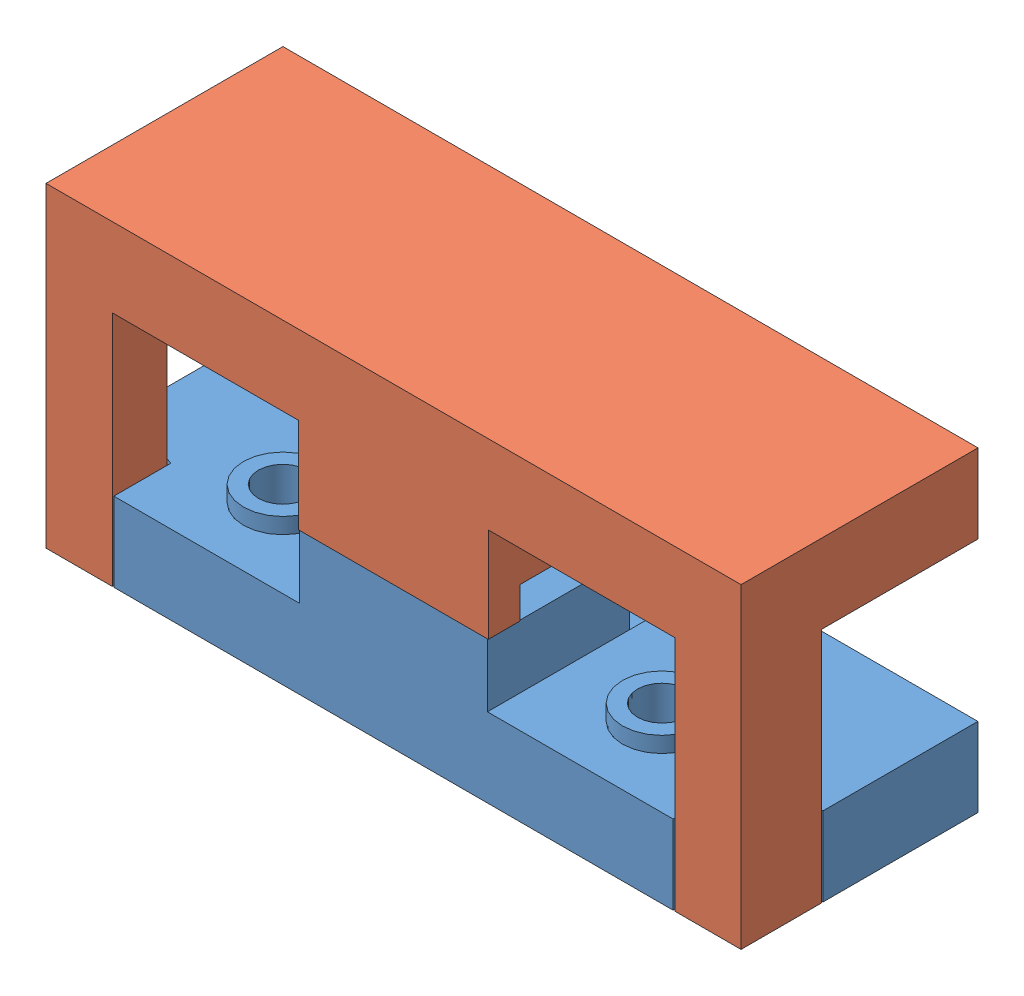
SolidWorks assembly Assem2, configuration Default. Lengths in mm.
Overall size (44.01 20 15).
2 component instances, 2 part files, 2 mates.
Components (placement in the parent):
- KneeJointBottom-1: KneeJointBottom [Default] at (-27.266 12.1131 64.1987) size (44 9 15)
- KneeJointBottom2-1: KneeJointBottom2 [Default] at (16.7396 32.1131 64.1987) x (-1 0 0) z (0 0 1) size (44 20 15)
Mates (geometry in assembly coordinates):
- Coincident9: coincident anti-aligned: plane of KneeJointBottom-1 through (-27.266 21.1131 64.1987) normal (0 1 0); plane of KneeJointBottom2-1 through (16.7396 21.1131 64.1987) normal (0 -1 0)
- Coincident11: coincident anti-aligned: line of KneeJointBottom-1 through (-11.216 21.1131 79.1987) axis (1 0 0); line of KneeJointBottom2-1 through (0.7396 21.1131 79.1987) axis (-1 0 0)
